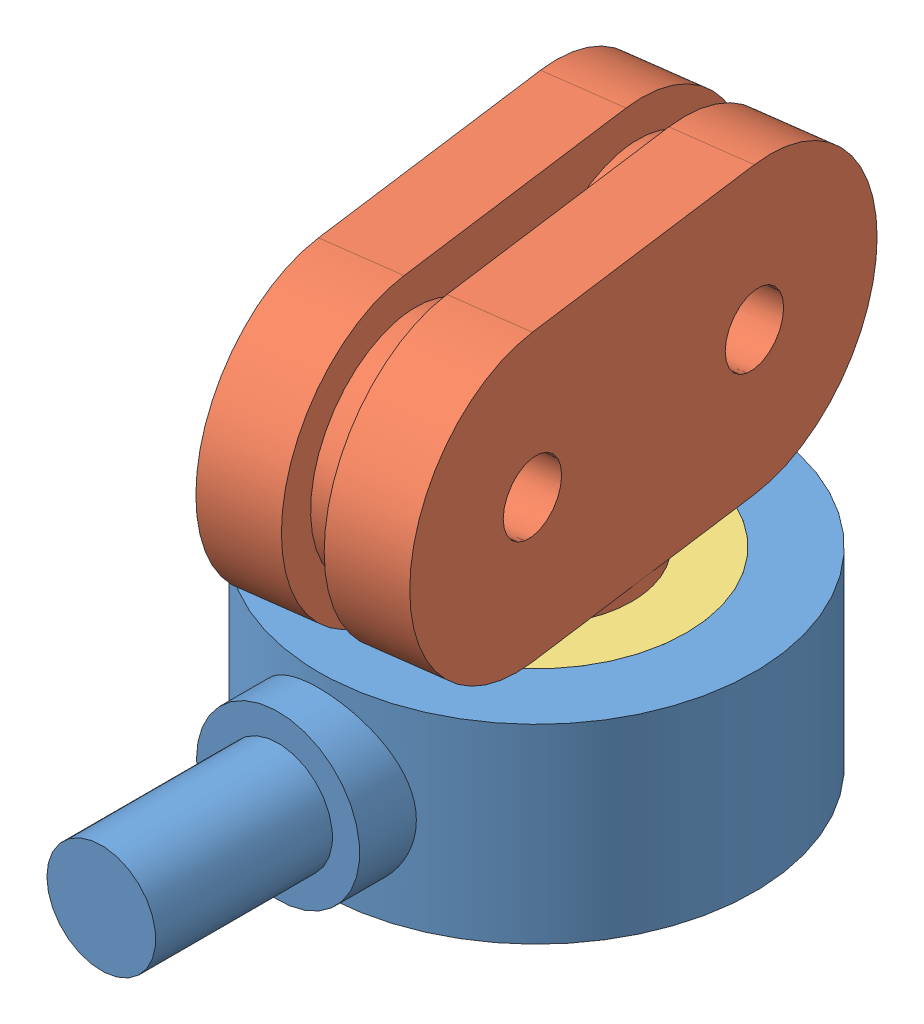
SolidWorks assembly 万向绳, configuration 默认. Lengths in mm.
Overall size (16 18.5 26.37).
4 component instances, 4 part files, 6 mates.
Components (placement in the parent):
- 万向绳2-1: 万向绳2 [默认] at (-97.2122 22.5289 -4) size (16 7 24)
- 万向绳1-1: 万向绳1 [默认] at (-93.1155 35.2789 0.2461) x (-0.132079 0 -0.991239) z (0 1 0) size (20 7 13.5)
- 万向绳3-1: 万向绳3 [默认] at (-97.2122 27.0289 -4) size (11 2.5 11)
- 万向绳4-1: 万向绳4 [默认] at (-97.2122 27.0289 -4) x (-0.837169 0 -0.546944) z (-0.546944 0 0.837169) size (8 5 8)
Mates (geometry in assembly coordinates):
- 同心1: concentric anti-aligned: cylinder of 万向绳1-1 through (-97.2122 27.0289 -4) axis (0 1 0) radius 3.5; cylinder of 万向绳3-1 through (-97.2122 29.5289 -4) axis (0 -1 0) radius 3.5
- 重合1: coincident anti-aligned: plane of 万向绳2-1 through (-97.2122 27.0289 -4) normal (0 1 0); plane of 万向绳3-1 through (-97.2122 27.0289 -4) normal (0 -1 0)
- 同心2: concentric anti-aligned: cylinder of 万向绳2-1 through (-97.2122 27.0289 -4) axis (0 1 0) radius 5.5; cylinder of 万向绳3-1 through (-97.2122 29.5289 -4) axis (0 -1 0) radius 5.5
- 重合2: coincident anti-aligned: plane of 万向绳3-1 through (-97.2122 27.0289 -4) normal (0 -1 0); plane of 万向绳4-1 through (-97.2122 27.0289 -4) normal (0 1 0)
- 同心3: concentric anti-aligned: cylinder of 万向绳2-1 through (-97.2122 29.5289 -4) axis (0 -1 0) radius 4; cylinder of 万向绳4-1 through (-97.2122 22.0289 -4) axis (0 1 0) radius 4
- 重合3: coincident anti-aligned: plane of 万向绳1-1 through (-93.1155 27.0289 0.2461) normal (0 -1 0); plane of 万向绳4-1 through (-97.2122 27.0289 -4) normal (0 1 0)
